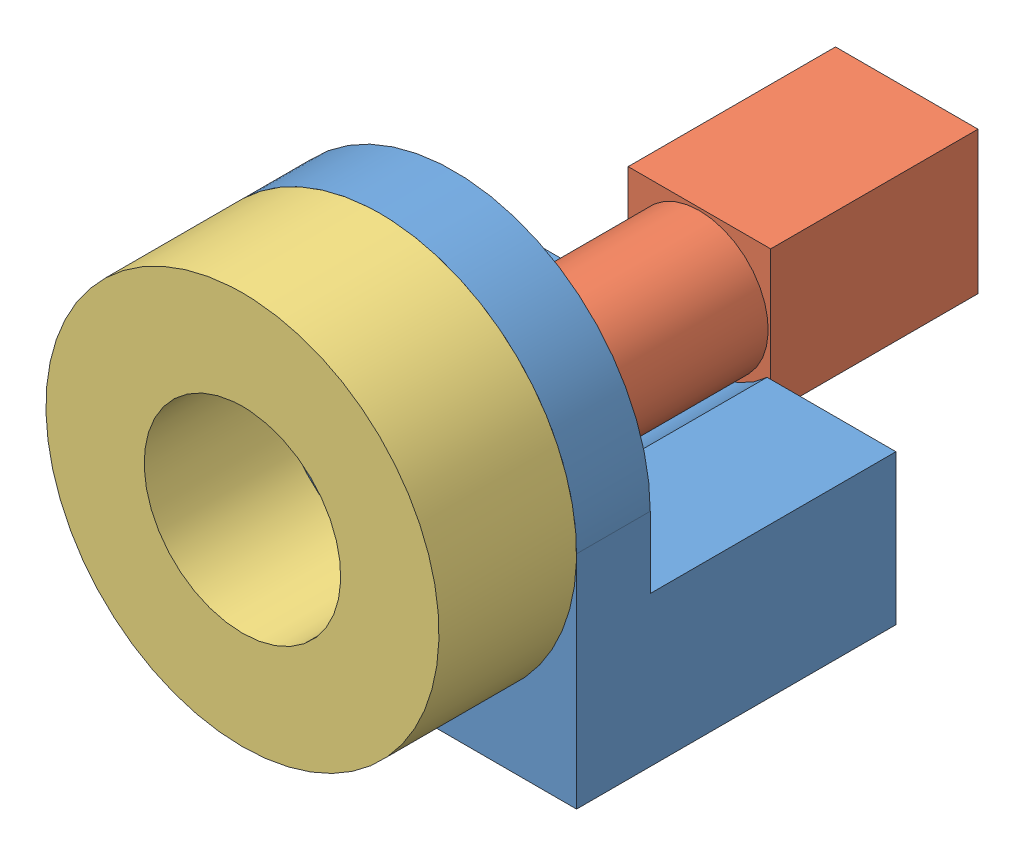
SolidWorks assembly assem1 cam and light, configuration Default. Lengths in mm.
Overall size (80 85 135.2).
3 component instances, 3 part files, 6 mates.
Components (placement in the parent):
- gá đèn-1: gá đèn [Default] at (42.9789 43.4214 54.1424) size (80 85 65)
- camera_basler-1: camera_basler [Default] at (28.4789 51.9214 -38.0576) x (1 0 0) z (0 -1 0) size (29 86.3 29)
- light white-1: light white [Default] at (42.9789 43.4214 97.1424) x (1 0 0) z (0 1 0) size (80 28 80)
Mates (geometry in assembly coordinates):
- Parallel1: parallel: plane of gá đèn-1 through (42.9789 -1.5786 69.1424) normal (0 -1 0); plane of camera_basler-1 through (28.4789 22.9214 1.8909) normal (0 -1 0)
- Tangent1: tangent: cylinder of gá đèn-1 through (42.9789 43.4214 69.1424) axis (0 0 -1) radius 20; cylinder of camera_basler-1 through (42.9789 37.4214 45.9909) axis (0 0 -1) radius 14
- Width1: width: plane of gá đèn-1 through (2.9789 43.4214 69.1424) normal (-1 0 0); plane of camera_basler-1 through (82.9789 43.4214 69.1424) normal (1 0 0); plane of gá đèn-1 through (57.4789 51.9214 1.8909) normal (1 0 0); plane of camera_basler-1 through (28.4789 51.9214 1.8909) normal (-1 0 0)
- Coincident1: coincident anti-aligned: plane of gá đèn-1 through (42.9789 43.4214 4.1424) normal (0 0 -1); plane of camera_basler-1 through (28.4789 51.9214 1.8909) normal (0 0 1)
- Concentric3: concentric: cylinder of gá đèn-1 through (42.9789 43.4214 69.1424) axis (0 0 -1) radius 20; cylinder of light white-1 through (42.9789 43.4214 85.6928) axis (0 0 1) radius 20
- Coincident2: coincident anti-aligned: plane of gá đèn-1 through (42.9789 43.4214 69.1424) normal (0 0 1); plane of light white-1 through (42.9789 43.4214 85.6928) normal (0 0 -1)
